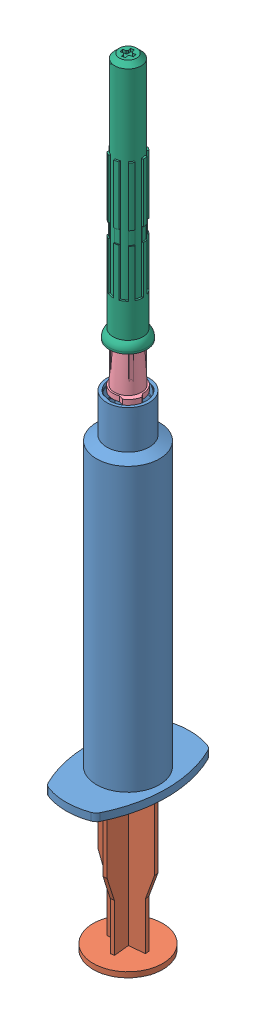
SolidWorks assembly Assem1, configuration Default. Lengths in mm.
Overall size (17.07 172.13 27.43).
6 component instances, 6 part files, 10 mates.
Components (placement in the parent):
- body-1: body [Default] at origin size (17.07 76.2 27.43)
- plunger-1: plunger [Default] at (0 -33.4402 0) x (-0.101269 0 -0.994859) z (0.994859 0 -0.101269) size (15.42 78.08 15.42)
- plunger_head-1: plunger_head [Default] at (0 38.3148 0) size (12.7 9.32 12.7)
- pin_mount-1: pin_mount [Default] at (0 73.914 0) x (0.573499 0 -0.819206) z (0.819206 0 0.573499) size (6.71 16.76 8.15)
- pin-1: pin [Default] at (0 85.344 0) x (-0.573499 0 0.819206) z (-0.819206 0 -0.573499) size (0.89 44.45 0.89)
- closure-1: closure [Default] at (0 83.8004 0) x (-0.188657 0 -0.982043) z (0.982043 0 -0.188657) size (8.33 54.86 8.33)
Mates (geometry in assembly coordinates):
- Coincident1: coincident anti-aligned: axis of body-1 through (0 0 0) axis (0 1 0); axis of plunger-1 through (0 47.3508 0) axis (0 -1 0)
- Coincident2: coincident anti-aligned: axis of body-1 through (0 1.6764 0) axis (0 -1 0); axis of plunger_head-1 through (0 38.3148 0) axis (0 1 0)
- Coincident4: coincident aligned: axis of body-1 through (0 0 0) axis (0 1 0); axis of pin_mount-1 through (0 73.914 0) axis (0 1 0)
- Coincident5: coincident anti-aligned: axis of body-1 through (0 0 0) axis (0 1 0); axis of pin-1 through (0 129.794 0) axis (0 -1 0)
- Coincident6: coincident anti-aligned: plane of pin_mount-1 through (0 73.914 0) normal (0.573499 0 -0.819206); plane of pin-1 through (0 85.344 0) normal (-0.573499 0 0.819206)
- Distance1: distance = 11.43 mm aligned: plane of pin_mount-1; plane of pin-1
- Coincident8: coincident anti-aligned: plane of plunger-1 through (-1.5162 38.3148 0.1543) normal (0 1 0); plane of plunger_head-1 through (0 38.3148 -2.5145) normal (0 -1 0)
- Coincident9: coincident aligned: plane of plunger_head-1 through (0 38.3148 0) normal (1 0 0); plane of assembly through (0 0 0) normal (1 0 0)
- Coincident10: coincident aligned: axis of plunger_head-1 through (0 38.3148 0) axis (0 1 0); axis of closure-1 through (0 83.8004 0) axis (0 1 0)
- Coincident11: coincident anti-aligned: plane of body-1 through (0 73.914 -4.7117) normal (0 1 0); plane of pin_mount-1 through (0 73.914 0) normal (0 -1 0)
